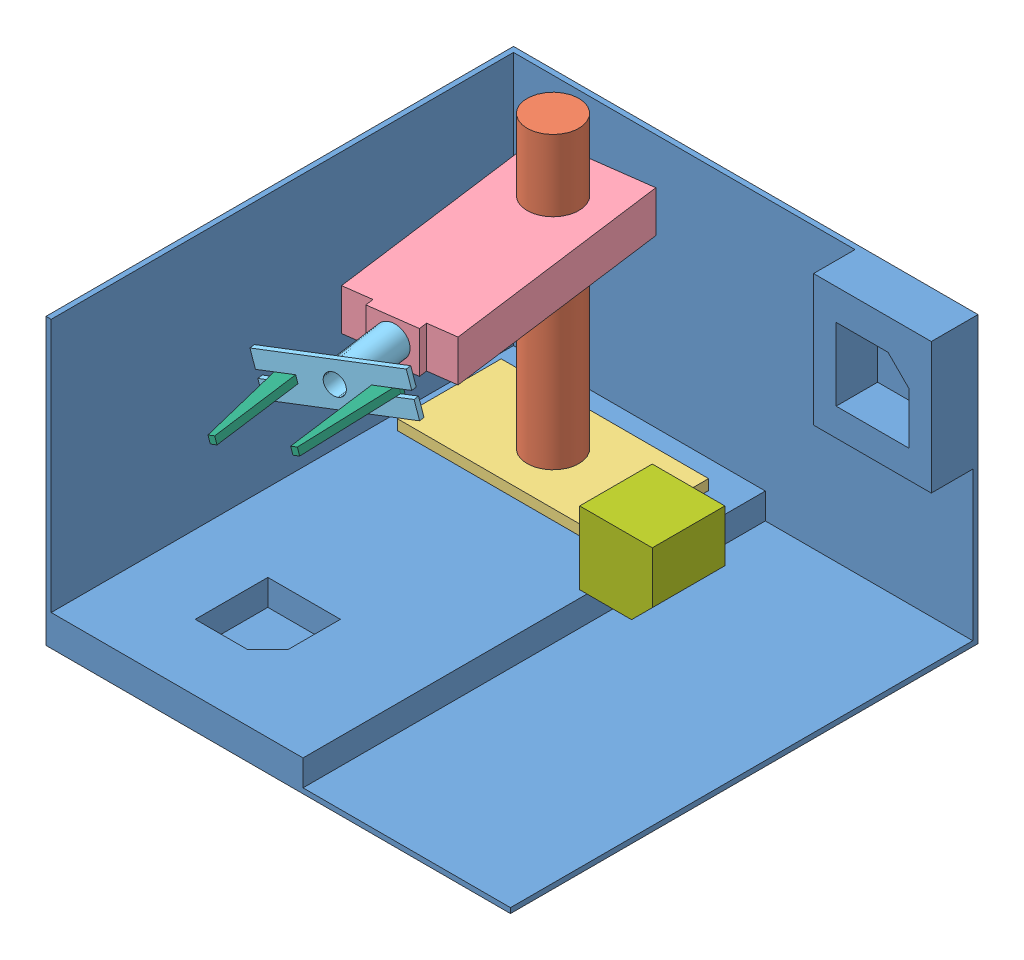
SolidWorks assembly Assem1, configuration Default. Lengths in mm.
Overall size (11520.55 8128 11450.1).
8 component instances, 7 part files, 9 mates.
Components (placement in the parent):
- CCBase-1: CCBase [Default] at origin size (11375.6 6981.21 11450.1)
- CCPin-1: CCPin [Default] at (-2636.7765 4318 -3641.7974) x (0.837169 0 0.546944) z (0 1 0) size (1270 1270 7620)
- CCPlate_01-1: CCPlate_01 [Default] at (-2636.7765 889 -3641.7974) x (1 0 0) z (0 -1 0) size (5080 2540 254)
- CCPlate_02-1: CCPlate_02 [Default] at (-2431.8721 5874.6447 -2106.0062) x (0.132248 0 0.991217) z (0 -1 0) size (5842 2540 1016)
- CCGripper-1: CCGripper [Default] at (-1813.7804 5874.6447 2526.6896) x (0.949912 0.285665 -0.126737) z (-0.283156 0.95833 0.037778) size (3556 3937 1016)
- Gripper_Arm-1: Gripper_Arm [Default] at (-2906.0786 5555.3857 2438.4075) x (0.283156 -0.95833 -0.037778) z (-0.949912 -0.285665 0.126737) size (279.4 2540 508)
- Gripper_Arm-2: Gripper_Arm [Default] at (-782.8346 6193.9037 2155.1255) x (-0.283156 0.95833 0.037778) z (0.949912 0.285665 -0.126737) size (279.4 2540 508)
- CCBlock-1: CCBlock [Default] at (4943.7528 5278.0679 1508.3145) size (1778 1778 1778)
Mates (geometry in assembly coordinates):
- ProfileCenter1: profile center = 0 mm aligned: circle of CCBase-1; circle of CCPin-1
- ProfileCenter2: profile center = 0 mm anti-aligned: circle of CCPlate_01-1; circle of CCBase-1
- Concentric1: concentric anti-aligned: cylinder of CCPin-1 through (-2636.7765 8128 -3641.7974) axis (0 -1 0) radius 635; cylinder of CCPlate_02-1 through (-2636.7765 5366.6447 -3641.7974) axis (0 1 0) radius 635
- LimitDistance1: limit distance = 4350.6447 mm anti-aligned: plane of CCPlate_01-1 through (-2636.7765 1016 -3641.7974) normal (0 1 0); plane of CCPlate_02-1 through (-2431.8721 5366.6447 -2106.0062) normal (0 -1 0)
- Concentric3: concentric aligned: cylinder of CCPlate_02-1 through (-2368.0494 5874.6447 -1627.645) axis (0.132248 0 0.991217) radius 381; cylinder of CCGripper-1 through (-1813.7804 5874.6447 2526.6896) axis (0.132248 0 0.991217) radius 381
- LimitDistance2: limit distance = 254.1466 mm anti-aligned: plane of CCPlate_02-1 through (-2368.0494 5874.6447 -1627.645) normal (0.132248 0 0.991217); plane of CCGripper-1 through (-2334.4392 5874.6447 -1375.7306) normal (-0.132248 0 -0.991217)
- Coincident5: coincident anti-aligned: plane of CCGripper-1 through (-1830.5758 5874.6447 2400.805) normal (-0.132248 0 -0.991217); plane of Gripper_Arm-1 through (-3108.303 5397.6313 2571.2787) normal (0.132248 0 0.991217)
- LimitDistance3: limit distance = 0 mm anti-aligned: plane of CCGripper-1 through (-2650.9201 5627.9445 2510.2549) normal (-0.949912 -0.285665 0.126737); plane of Gripper_Arm-1 through (-2664.8009 5627.9445 2406.2164) normal (0.949912 0.285665 -0.126737)
- Coincident7: coincident anti-aligned: plane of CCGripper-1 through (-1855.7484 5959.8402 2404.1636) normal (0.283156 -0.95833 -0.037778); plane of Gripper_Arm-1 through (-2836.62 5568.0223 4991.6477) normal (-0.283156 0.95833 0.037778)
